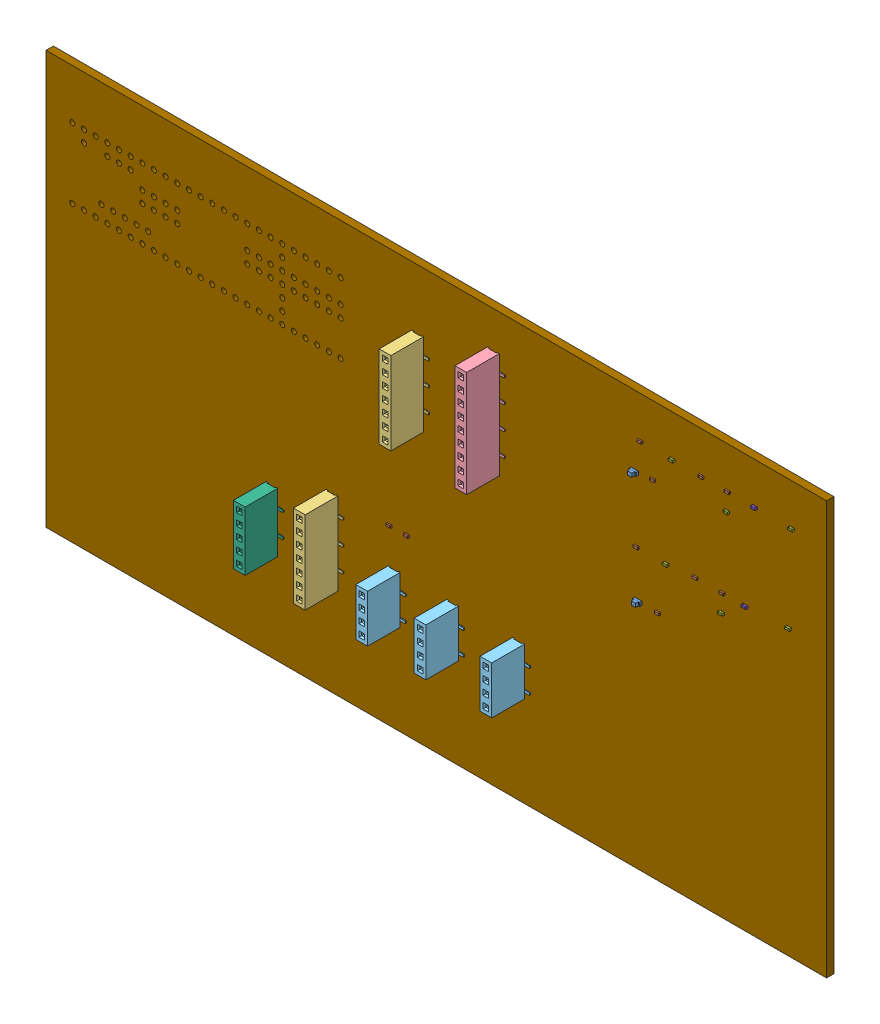
SolidWorks assembly Raitong_Env_Sensor, configuration Default. Lengths in mm.
Overall size (170 90 9.05).
56 component instances, 9 part files, 0 mates.
Components (placement in the parent):
- Raitong_Env_Sensor.step-1: Raitong_Env_Sensor.step [Default] at origin size (170 90 9.05)
  - LED_0603_1608Metric.step-1: LED_0603_1608Metric.step [Default] at (141.7575 55.88 1.6502) size (1.6 0.8 1.1)
    - SOLID.step-1: SOLID.step [Default] at origin size (1.6 0.8 1.1)
  - LED_0603_1608Metric.step-2: LED_0603_1608Metric.step [Default] at (140.97 80.01 1.6502) size (1.6 0.8 1.1)
    - SOLID.step-1: SOLID.step [Default] at origin size (1.6 0.8 1.1)
  - R_0402_1005Metric.step-1: R_0402_1005Metric.step [Default] at (145.0152 80.4986 1.6502) x (-1 0 0) z (0 0 1) size (1 0.5 0.35)
    - SOLID-0.step-1: SOLID-0.step [Default] at origin size (1 0.5 0.35)
  - R_0402_1005Metric.step-2: R_0402_1005Metric.step [Default] at (87.63 43.18 1.6502) size (1 0.5 0.35)
    - SOLID-0.step-1: SOLID-0.step [Default] at origin size (1 0.5 0.35)
  - R_0402_1005Metric.step-3: R_0402_1005Metric.step [Default] at (91.44 43.18 1.6502) x (-1 0 0) z (0 0 1) size (1 0.5 0.35)
    - SOLID-0.step-1: SOLID-0.step [Default] at origin size (1 0.5 0.35)
  - R_0402_1005Metric.step-4: R_0402_1005Metric.step [Default] at (146.05 55.88 1.6502) x (-1 0 0) z (0 0 1) size (1 0.5 0.35)
    - SOLID-0.step-1: SOLID-0.step [Default] at origin size (1 0.5 0.35)
  - PinSocket_1x07_P2.54mm_Vertical_SMD_Pin1Left.step-1: PinSocket_1x07_P2.54mm_Vertical_SMD_Pin1Left.step [Default] at (75.31 34.29 1.6502) size (4.64 17.98 7.4)
    - SOLID-1.step-1: SOLID-1.step [Default] at origin size (4.64 17.98 7.4)
  - PinSocket_1x09_P2.54mm_Vertical_SMD_Pin1Left.step-1: PinSocket_1x09_P2.54mm_Vertical_SMD_Pin1Left.step [Default] at (110.49 76.2 1.6502) size (4.64 23.06 7.4)
    - SOLID-2.step-1: SOLID-2.step [Default] at origin size (4.64 23.06 7.4)
  - PinSocket_1x04_P2.54mm_Vertical_SMD_Pin1Left.step-1: PinSocket_1x04_P2.54mm_Vertical_SMD_Pin1Left.step [Default] at (115.95 30.48 1.6502) size (4.64 10.36 7.4)
    - SOLID-3.step-1: SOLID-3.step [Default] at origin size (4.64 10.36 7.4)
  - PinSocket_1x04_P2.54mm_Vertical_SMD_Pin1Left.step-2: PinSocket_1x04_P2.54mm_Vertical_SMD_Pin1Left.step [Default] at (88.9 30.48 1.6502) size (4.64 10.36 7.4)
    - SOLID-3.step-1: SOLID-3.step [Default] at origin size (4.64 10.36 7.4)
  - PinSocket_1x05_P2.54mm_Vertical_SMD_Pin1Left.step-1: PinSocket_1x05_P2.54mm_Vertical_SMD_Pin1Left.step [Default] at (62.23 31.75 1.6502) size (4.64 12.9 7.4)
    - SOLID-4.step-1: SOLID-4.step [Default] at origin size (4.64 12.9 7.4)
  - PinSocket_1x07_P2.54mm_Vertical_SMD_Pin1Left.step-2: PinSocket_1x07_P2.54mm_Vertical_SMD_Pin1Left.step [Default] at (93.98 73.66 1.6502) size (4.64 17.98 7.4)
    - SOLID-1.step-1: SOLID-1.step [Default] at origin size (4.64 17.98 7.4)
  - C_0402_1005Metric.step-1: C_0402_1005Metric.step [Default] at (149.225 86.36 1.6502) x (-1 0 0) z (0 0 1) size (1 0.5 0.5)
    - SOLID-5.step-1: SOLID-5.step [Default] at origin size (1 0.5 0.5)
  - C_0402_1005Metric.step-2: C_0402_1005Metric.step [Default] at (161.14 82.55 1.6502) size (1 0.5 0.5)
    - SOLID-5.step-1: SOLID-5.step [Default] at origin size (1 0.5 0.5)
  - C_0402_1005Metric.step-3: C_0402_1005Metric.step [Default] at (175.26 86.36 1.6502) size (1 0.5 0.5)
    - SOLID-5.step-1: SOLID-5.step [Default] at origin size (1 0.5 0.5)
  - C_0402_1005Metric.step-4: C_0402_1005Metric.step [Default] at (147.955 66.04 1.6502) size (1 0.5 0.5)
    - SOLID-5.step-1: SOLID-5.step [Default] at origin size (1 0.5 0.5)
  - C_0402_1005Metric.step-5: C_0402_1005Metric.step [Default] at (160.02 62.865 1.6502) x (-1 0 0) z (0 0 1) size (1 0.5 0.5)
    - SOLID-5.step-1: SOLID-5.step [Default] at origin size (1 0.5 0.5)
  - C_0402_1005Metric.step-6: C_0402_1005Metric.step [Default] at (174.625 67.31 1.6502) size (1 0.5 0.5)
    - SOLID-5.step-1: SOLID-5.step [Default] at origin size (1 0.5 0.5)
  - L_0402_1005Metric.step-1: L_0402_1005Metric.step [Default] at (167.155 86.36 1.6502) size (1 0.5 0.5)
    - SOLID-6.step-1: SOLID-6.step [Default] at origin size (1 0.5 0.5)
  - L_0402_1005Metric.step-2: L_0402_1005Metric.step [Default] at (165.1 66.675 1.6502) size (1 0.5 0.5)
    - SOLID-6.step-1: SOLID-6.step [Default] at origin size (1 0.5 0.5)
  - R_0402_1005Metric.step-5: R_0402_1005Metric.step [Default] at (142.24 86.36 1.6502) x (-1 0 0) z (0 0 1) size (1 0.5 0.35)
    - SOLID-0.step-1: SOLID-0.step [Default] at origin size (1 0.5 0.35)
  - R_0402_1005Metric.step-6: R_0402_1005Metric.step [Default] at (161.29 86.36 1.6502) x (-1 0 0) z (0 0 1) size (1 0.5 0.35)
    - SOLID-0.step-1: SOLID-0.step [Default] at origin size (1 0.5 0.35)
  - R_0402_1005Metric.step-7: R_0402_1005Metric.step [Default] at (155.575 86.36 1.6502) x (-1 0 0) z (0 0 1) size (1 0.5 0.35)
    - SOLID-0.step-1: SOLID-0.step [Default] at origin size (1 0.5 0.35)
  - R_0402_1005Metric.step-8: R_0402_1005Metric.step [Default] at (141.455 66.04 1.6502) size (1 0.5 0.35)
    - SOLID-0.step-1: SOLID-0.step [Default] at origin size (1 0.5 0.35)
  - R_0402_1005Metric.step-9: R_0402_1005Metric.step [Default] at (154.305 66.675 1.6502) size (1 0.5 0.35)
    - SOLID-0.step-1: SOLID-0.step [Default] at origin size (1 0.5 0.35)
  - R_0402_1005Metric.step-10: R_0402_1005Metric.step [Default] at (160.17 66.675 1.6502) size (1 0.5 0.35)
    - SOLID-0.step-1: SOLID-0.step [Default] at origin size (1 0.5 0.35)
  - PinSocket_1x04_P2.54mm_Vertical_SMD_Pin1Left.step-3: PinSocket_1x04_P2.54mm_Vertical_SMD_Pin1Left.step [Default] at (101.6 30.48 1.6502) size (4.64 10.36 7.4)
    - SOLID-3.step-1: SOLID-3.step [Default] at origin size (4.64 10.36 7.4)
  - COMPOUND.step-1: COMPOUND.step [Default] at origin size (170 90 1.6)
